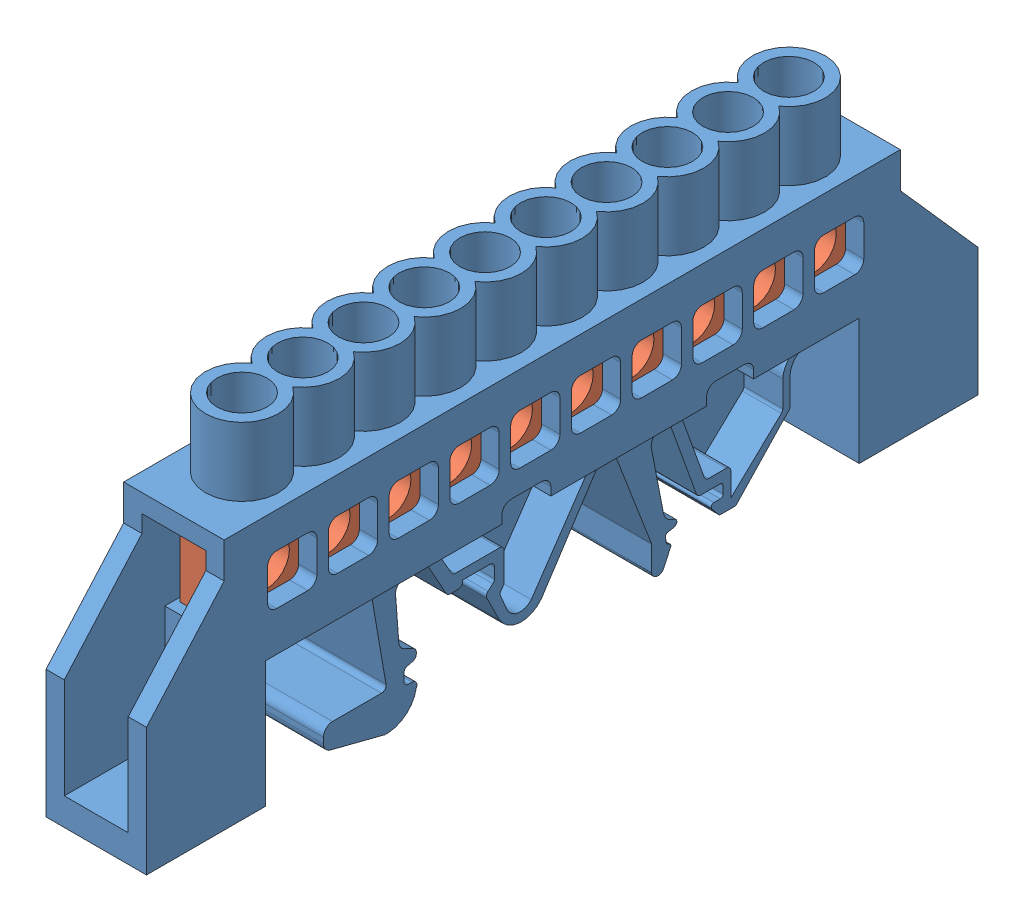
SolidWorks assembly MONTAGEM BARRAMENTO 10 FUROS, configuration Valor predeterminado. Lengths in mm.
Overall size (11 35 91).
12 component instances, 3 part files, 22 mates.
Components (placement in the parent):
- revestimento de plástico-1: revestimento de plástico [Valor predeterminado] at (12.532 -12.1261 87.1938) size (11 35 91)
- barra de cobre-1: barra de cobre [Valor predeterminado] at (15.4627 3.3739 7.9848) size (6 10 67)
- parafudo-1: parafudo [Valor predeterminado] at (12.4627 13.3739 11.6348) size (5.01 10.01 5.03)
- parafudo-2: parafudo [Valor predeterminado] at (12.4627 13.3739 18.2848) size (5.01 10.01 5.03)
- parafudo-3: parafudo [Valor predeterminado] at (12.4627 13.3739 24.9348) size (5.01 10.01 5.03)
- parafudo-4: parafudo [Valor predeterminado] at (12.4627 13.3739 31.5848) size (5.01 10.01 5.03)
- parafudo-5: parafudo [Valor predeterminado] at (12.4627 13.3739 38.2348) size (5.01 10.01 5.03)
- parafudo-6: parafudo [Valor predeterminado] at (12.4627 13.3739 44.8848) size (5.01 10.01 5.03)
- parafudo-7: parafudo [Valor predeterminado] at (12.4627 13.3739 51.5348) size (5.01 10.01 5.03)
- parafudo-8: parafudo [Valor predeterminado] at (12.4627 13.3739 58.1848) size (5.01 10.01 5.03)
- parafudo-9: parafudo [Valor predeterminado] at (12.4627 13.3739 64.8348) size (5.01 10.01 5.03)
- parafudo-10: parafudo [Valor predeterminado] at (12.4627 13.3739 71.4848) size (5.01 10.01 5.03)
Mates (geometry in assembly coordinates):
- Concêntrico1: concentric aligned: cylinder of barra de cobre-1 through (12.4627 7.3739 11.6348) axis (0 1 0) radius 2; cylinder of parafudo-1 through (12.4627 5.3739 11.6348) axis (0 1 0) radius 2
- Concêntrico2: concentric aligned: cylinder of barra de cobre-1 through (12.4627 7.3739 18.2848) axis (0 1 0) radius 2; cylinder of parafudo-2 through (12.4627 5.3739 18.2848) axis (0 1 0) radius 2
- Concêntrico3: concentric aligned: cylinder of barra de cobre-1 through (12.4627 7.3739 24.9348) axis (0 1 0) radius 2; cylinder of parafudo-3 through (12.4627 5.3739 24.9348) axis (0 1 0) radius 2
- Concêntrico4: concentric aligned: cylinder of barra de cobre-1 through (12.4627 7.3739 31.5848) axis (0 1 0) radius 2; cylinder of parafudo-4 through (12.4627 5.3739 31.5848) axis (0 1 0) radius 2
- Concêntrico5: concentric aligned: cylinder of barra de cobre-1 through (12.4627 7.3739 38.2348) axis (0 1 0) radius 2; cylinder of parafudo-5 through (12.4627 5.3739 38.2348) axis (0 1 0) radius 2
- Concêntrico6: concentric aligned: cylinder of barra de cobre-1 through (12.4627 7.3739 44.8848) axis (0 1 0) radius 2; cylinder of parafudo-6 through (12.4627 5.3739 44.8848) axis (0 1 0) radius 2
- Concêntrico7: concentric aligned: cylinder of barra de cobre-1 through (12.4627 7.3739 51.5348) axis (0 1 0) radius 2; cylinder of parafudo-7 through (12.4627 5.3739 51.5348) axis (0 1 0) radius 2
- Coincidente1: coincident aligned: circle of barra de cobre-1; cylinder of parafudo-8 through (12.4627 5.3739 58.1848) axis (0 1 0) radius 2
- Concêntrico8: concentric aligned: cylinder of barra de cobre-1 through (12.4627 7.3739 64.8348) axis (0 1 0) radius 2; cylinder of parafudo-9 through (12.4627 5.3739 64.8348) axis (0 1 0) radius 2
- Coincidente2: coincident aligned: circle of barra de cobre-1; cylinder of parafudo-10 through (12.4627 5.3739 71.4848) axis (0 1 0) radius 2
- Coincidente3: coincident anti-aligned: plane of barra de cobre-1 through (15.4627 13.3739 74.9848) normal (0 1 0); plane of parafudo-10 through (12.4627 13.3739 71.4848) normal (0 -1 0)
- Coincidente4: coincident aligned: plane of parafudo-9 through (12.4627 15.3739 64.8348) normal (0 1 0); plane of parafudo-10 through (12.4627 15.3739 71.4848) normal (0 1 0)
- Coincidente5: coincident aligned: plane of parafudo-8 through (12.4627 15.3739 58.1848) normal (0 1 0); plane of parafudo-9 through (12.4627 15.3739 64.8348) normal (0 1 0)
- Coincidente6: coincident aligned: plane of parafudo-7 through (12.4627 15.3739 51.5348) normal (0 1 0); plane of parafudo-8 through (12.4627 15.3739 58.1848) normal (0 1 0)
- Coincidente7: coincident aligned: plane of parafudo-6 through (12.4627 15.3739 44.8848) normal (0 1 0); plane of parafudo-7 through (12.4627 15.3739 51.5348) normal (0 1 0)
- Coincidente8: coincident aligned: plane of parafudo-5 through (12.4627 15.3739 38.2348) normal (0 1 0); plane of parafudo-6 through (12.4627 15.3739 44.8848) normal (0 1 0)
- Coincidente9: coincident aligned: plane of parafudo-4 through (12.4627 15.3739 31.5848) normal (0 1 0); plane of parafudo-5 through (12.4627 15.3739 38.2348) normal (0 1 0)
- Coincidente10: coincident aligned: plane of parafudo-3 through (12.4627 15.3739 24.9348) normal (0 1 0); plane of parafudo-4 through (12.4627 15.3739 31.5848) normal (0 1 0)
- Coincidente11: coincident aligned: plane of parafudo-2 through (12.4627 15.3739 18.2848) normal (0 1 0); plane of parafudo-3 through (12.4627 15.3739 24.9348) normal (0 1 0)
- Coincidente12: coincident aligned: plane of parafudo-1 through (12.4627 15.3739 11.6348) normal (0 1 0); plane of parafudo-2 through (12.4627 15.3739 18.2848) normal (0 1 0)
- Coincidente13: coincident anti-aligned: plane of revestimento de plástico-1 through (16.032 3.3739 88.1938) normal (0 1 0); plane of barra de cobre-1 through (15.4627 3.3739 74.9848) normal (0 -1 0)
- Tangente1: tangent: cylinder of revestimento de plástico-1 through (12.532 22.8739 71.2444) axis (0 -1 0) radius 2.75; face of parafudo-10
